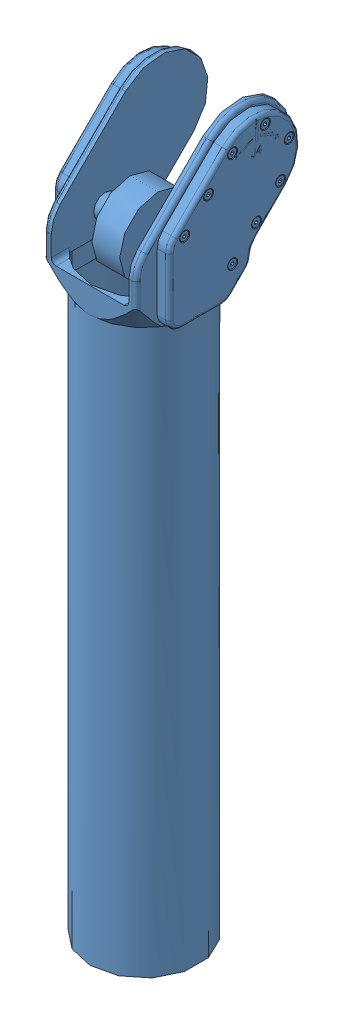
SolidWorks assembly B2650, configuration Default. Lengths in mm.
Overall size (96.33 590 129.5).
6 component instances, 3 part files, 3 mates.
Components (placement in the parent):
- B2126-3: B2126 [Default] at origin size (96.33 590 129.5)
- B1995-1: B1995 [woLabels] at (0 550 -45) x (0 0 -1) z (-1 0 0) size (239.39 157.62 264.32) (suppressed, hidden)
  - B1998-1: B1998 [X] x (0 0 -1) z (1 0 0) size (28.64 28.64 210)
  - B1998-2: B1998 [Y] x (0 0 1) z (0 1 0) size (28.64 28.64 110)
  - B1998-3: B1998 [Z] at origin size (28.64 28.64 260)
  - B1999-2: B1999 [100] at (0 0 197.2124) x (0 0 -1) z (0.268665 -0.963234 0) size (50 78.75 105)
Mates (geometry in assembly coordinates):
- Coincident1: coincident anti-aligned: plane of assembly through (0 0 0) normal (1 0 0)
- Concentric1: concentric anti-aligned: cylinder of B2126-3 through (-116.6688 550 -45) axis (1 0 0) radius 40; cylinder of B1995-1/B1998-3 through (-350 550 -45) axis (-1 0 0) radius 3
- Parallel1: parallel anti-aligned: plane of B1995-1; plane of assembly
